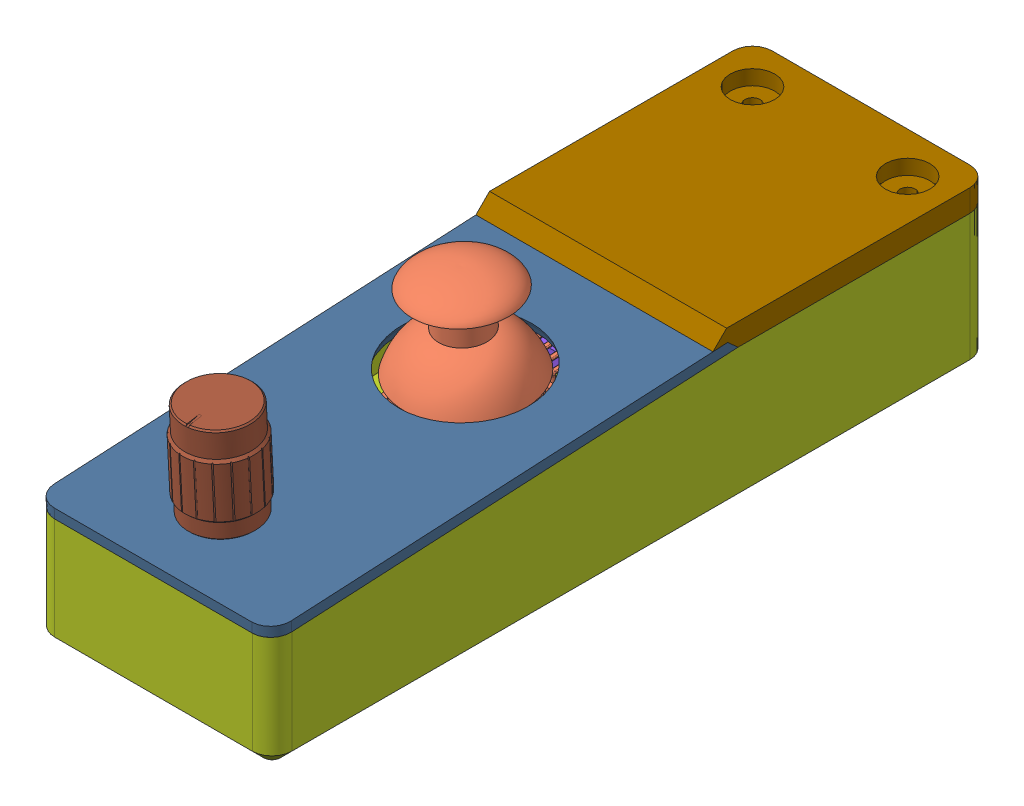
SolidWorks assembly CAD Mouse, configuration Default. Lengths in mm.
Overall size (48 47.57 145.38).
12 component instances, 11 part files, 22 mates.
Components (placement in the parent):
- arduinoMicro-2: arduinoMicro [Detailed] at (15.9134 30.6185 37.0903) x (0 0 1) z (1 0 0) size (49.35 17.5 18)
- Joystick HW504 Board-1: Joystick HW504 Board [Varsayılan] at (14.4134 34.5049 89.1552) x (1 0 0) z (0 -0.052336 0.99863) size (27.5 32.05 39.5)
- KY-040 Rotary Encoder-1: KY-040 Rotary Encoder [Default] at (21.1063 31.0072 150.8329) x (-1 0 0) z (0 0.052336 -0.99863) size (18.7 30.1 31.47)
  - Rotary Encoder-1: Rotary Encoder [Default] at (5.1929 2.265 12.688) size (11.8 14.9 15)
  - D-handle-1: D-handle [Default] at (5.1929 8.865 12.688) x (-0.994918 0 0.100689) z (-0.100689 0 -0.994918) size (6 20.2 6)
  - pcb-1: pcb [Default] at (-5.1071 1.765 2.138) x (0 0 1) z (-1 0 0) size (26.2 1.02 18.7)
  - 2.54 5PIN 90-1: 2.54 5PIN 90 [Default] at (-0.1071 2.265 26.008) x (-1 0 0) z (0 0 -1) size (12.7 7.32 8.85)
- Case Bottom-1: Case Bottom [Default] at origin size (48 28 145.28)
- Arduino Micro Lid^CAD Mouse-1: Arduino Micro Lid^CAD Mouse [Default] at (0 33.5685 0) x (1 0 0) z (0 1 0) size (32.54 7.02 5.65) (virtual)
- Top Panel^CAD Mouse-1: Top Panel^CAD Mouse [Default] at (-4.0866 0 0) x (0 0 -1) z (1 0 0) size (56 7.7 48) (virtual)
- Front Panel^CAD Mouse-2: Front Panel^CAD Mouse [Default] at (0 51.0536 2.6756) x (1 0 0) z (0 0.99863 0.052336) size (48 94.47 3.8) (virtual)
- Knob-1: Knob [Default] at (15.9134 47.5544 138.9948) x (0.994918 0.00527 -0.100551) z (0.100689 -0.05207 0.993554) size (14.91 19.72 14.92)
Mates (geometry in assembly coordinates):
- Parallel3: parallel anti-aligned: plane of KY-040 Rotary Encoder-1/pcb-1 through (26.2134 32.3824 148.7641) normal (0 -0.99863 -0.052336)
- Coincident3: coincident aligned: plane of Joystick HW504 Board-1 through (15.9134 34.5049 89.1552) normal (1 0 0); plane of arduinoMicro-2 through (15.9134 30.6185 37.0903) normal (1 0 0)
- Coincident4: coincident anti-aligned: plane of arduinoMicro-2 through (15.9134 30.6185 37.0903) normal (1 0 0); plane of KY-040 Rotary Encoder-1 through (15.9134 31.0072 150.8329) normal (-1 0 0)
- Coincident7: coincident anti-aligned: plane of Joystick HW504 Board-1 through (14.4134 48.4858 89.8879) normal (0 -0.99863 -0.052336)
- Coincident14: coincident: plane of Joystick HW504 Board-1 through (9.8634 39.3238 73.6362) normal (0 0.052336 -0.99863); line of Case Bottom-1 through (15.9134 42.3696 73.7958) axis (0 -0.99863 -0.052336)
- Coincident15: coincident: plane of KY-040 Rotary Encoder-1 through (21.1063 32.4207 123.862) normal (0 0.052336 -0.99863); line of Case Bottom-1 through (15.9134 38.1778 124.1637) axis (0 0.99863 0.052336)
- Coincident16: coincident: plane of KY-040 Rotary Encoder-1/2.54 5PIN 90-1 through (21.2134 39.4237 125.2304) normal (0 0.99863 0.052336); line of Case Bottom-1 through (15.9134 39.476 124.2317) axis (0 0.052336 -0.99863)
- InPlace1: in place: plane of Case Bottom-1 through (21.9134 33.5685 28.5248) normal (0 1 0); plane of Arduino Micro Lid^CAD Mouse-1 through (0 33.5685 0) normal (0 1 0); moOrthogonalPlaneRef_w of Case Bottom-1 through (21.9134 33.5685 28.5248) normal (0 1 0); plane of Arduino Micro Lid^CAD Mouse-1 through (0 33.5685 0) normal (0 0 -1); plane of Case Bottom-1 through (21.9134 33.5685 28.5248) normal (0 1 0); plane of Arduino Micro Lid^CAD Mouse-1 through (0 33.5685 0) normal (1 0 0); plane of Case Bottom-1 through (21.9134 33.5685 28.5248) normal (0 1 0); unknown of Arduino Micro Lid^CAD Mouse-1
- Coincident17: coincident aligned: plane of Case Bottom-1; plane of Arduino Micro Lid^CAD Mouse-1
- Coincident18: coincident aligned: moOrthogonalPlaneRef_w of Case Bottom-1 through (0 33.5685 0) normal (0 0 -1); plane of Arduino Micro Lid^CAD Mouse-1 through (0 33.5685 0) normal (0 0 -1)
- Coincident19: coincident anti-aligned: moOrthogonalPlaneRef_w of Case Bottom-1 through (0 33.5685 0) normal (-1 0 0); plane of Arduino Micro Lid^CAD Mouse-1 through (0 33.5685 0) normal (1 0 0)
- InPlace3: in place: plane of Case Bottom-1 through (-4.0866 0 0) normal (1 0 0); plane of Top Panel^CAD Mouse-1 through (-4.0866 0 0) normal (1 0 0); plane of Case Bottom-1 through (-4.0866 0 0) normal (1 0 0); plane of Top Panel^CAD Mouse-1 through (-4.0866 0 0) normal (0 1 0); plane of Case Bottom-1 through (-4.0866 0 0) normal (1 0 0); plane of Top Panel^CAD Mouse-1 through (-4.0866 0 0) normal (0 0 -1); plane of Case Bottom-1 through (-4.0866 0 0) normal (1 0 0); unknown of Top Panel^CAD Mouse-1
- Coincident17: coincident aligned: plane of Case Bottom-1; plane of Top Panel^CAD Mouse-1
- Coincident18: coincident aligned: moOrthogonalPlaneRef_w of Case Bottom-1 through (-4.0866 0 0) normal (0 1 0); plane of Top Panel^CAD Mouse-1 through (-4.0866 0 0) normal (0 1 0)
- Coincident19: coincident anti-aligned: moOrthogonalPlaneRef_w of Case Bottom-1 through (-4.0866 0 0) normal (0 0 1); plane of Top Panel^CAD Mouse-1 through (-4.0866 0 0) normal (0 0 -1)
- InPlace4: in place: plane of Case Bottom-1 through (-8.0866 48.1185 58.6803) normal (0 0.99863 0.052336); plane of Front Panel^CAD Mouse-2 through (0 51.0536 2.6756) normal (0 0.99863 0.052336); plane of Case Bottom-1 through (-8.0866 48.1185 58.6803) normal (0 0.99863 0.052336); plane of Front Panel^CAD Mouse-2 through (0 51.0536 2.6756) normal (0 0.052336 -0.99863); plane of Case Bottom-1 through (-8.0866 48.1185 58.6803) normal (0 0.99863 0.052336); plane of Front Panel^CAD Mouse-2 through (0 51.0536 2.6756) normal (1 0 0); plane of Case Bottom-1 through (-8.0866 48.1185 58.6803) normal (0 0.99863 0.052336); unknown of Front Panel^CAD Mouse-2
- Coincident17: coincident aligned: plane of Case Bottom-1; plane of Front Panel^CAD Mouse-2
- Coincident18: coincident aligned: moOrthogonalPlaneRef_w of Case Bottom-1 through (0 51.0536 2.6756) normal (0 0.052336 -0.99863); plane of Front Panel^CAD Mouse-2 through (0 51.0536 2.6756) normal (0 0.052336 -0.99863)
- Coincident19: coincident anti-aligned: moOrthogonalPlaneRef_w of Case Bottom-1 through (0 51.0536 2.6756) normal (-1 0 0); plane of Front Panel^CAD Mouse-2 through (0 51.0536 2.6756) normal (1 0 0)
- Concentric1: concentric aligned: cylinder of KY-040 Rotary Encoder-1/D-handle-1 through (15.9134 60.6964 139.6835) axis (0 -0.99863 -0.052336) radius 3; cylinder of Knob-1 through (15.9134 67.2474 140.0268) axis (0 -0.99863 -0.052336) radius 6.455
- Parallel4: parallel anti-aligned: plane of KY-040 Rotary Encoder-1/D-handle-1 through (13.1775 49.7759 137.8787) normal (-0.100689 0.05207 -0.993554); plane of Knob-1 through (18.1824 67.3485 138.1365) normal (0.100689 -0.05207 0.993554)
- Distance1: distance = 13.64 mm anti-aligned: plane of KY-040 Rotary Encoder-1/pcb-1 through (26.2134 33.381 148.8164) normal (0 0.99863 0.052336); plane of Knob-1 through (15.9134 47.5544 138.9948) normal (0 -0.99863 -0.052336)
